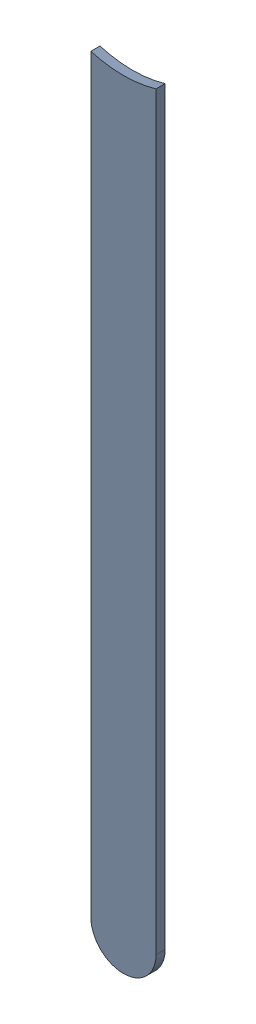
SolidWorks assembly Track (18.034mm,45.033mm)(18.034mm,48.387mm) on Bottom Layer, configuration Predeterminado. Lengths in mm.
Overall size (0.25 3.05 0.04).
2 component instances, 1 part files, 0 mates.
Components (placement in the parent):
- Track (18.034mm,45.033mm)(18.034mm,48.387mm) on Bottom Layer-1-1: Track (18.034mm,45.033mm)(18.034mm,48.387mm) on Bottom Layer-1 [Predeterminado] at (-68.317 -44.187 -0.4013) size (0.25 3.05 0.04)
  - Track (18.034mm,45.033mm)(18.034mm,48.387mm) on Bottom Layer-Part-1-1: Track (18.034mm,45.033mm)(18.034mm,48.387mm) on Bottom Layer-Part-1 [Predeterminado] at origin size (0.25 3.05 0.04)
